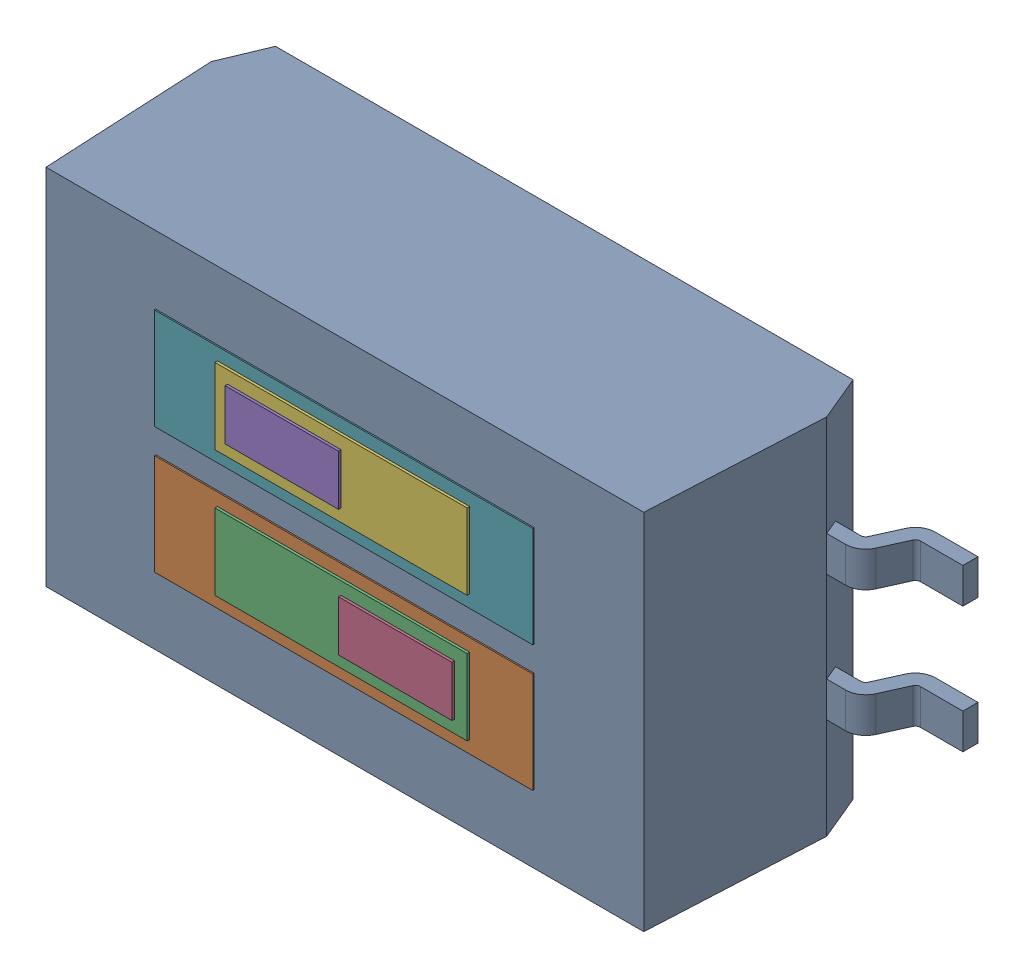
SolidWorks assembly S1, configuration Default. Lengths in mm.
Overall size (8.13 3.66 2.38).
13 component instances, 4 part files, 0 mates.
Components (placement in the parent):
- c-1571983-01-b-3d-1: c-1571983-01-b-3d [Default] at (63.7533 2.9696 0.571) x (0 1 0) z (0 0 1) size (3.66 8.13 2.31)
- 870942400-1: 870942400 [Default] at (63.7532 2.3346 1.27) size (3.81 1.02 1.07)
  - Extruded_11-1: Extruded_11 [Default] at origin size (3.81 1.02 1.07)
- 870942560-1: 870942560 [Default] at (63.7532 2.3346 1.27) size (2.54 0.76 1.09)
  - Extruded_12-1: Extruded_12 [Default] at origin size (2.54 0.76 1.09)
- 870942720-1: 870942720 [Default] at (64.3247 2.3346 1.27) size (1.14 0.51 1.12)
  - Extruded_13-1: Extruded_13 [Default] at origin size (1.14 0.51 1.12)
- 870942720-2: 870942720 [Default] at (63.1817 3.6046 1.27) size (1.14 0.51 1.12)
  - Extruded_13-1: Extruded_13 [Default] at origin size (1.14 0.51 1.12)
- 870942560-2: 870942560 [Default] at (63.7532 3.6046 1.27) size (2.54 0.76 1.09)
  - Extruded_12-1: Extruded_12 [Default] at origin size (2.54 0.76 1.09)
- 870942400-2: 870942400 [Default] at (63.7532 3.6046 1.27) size (3.81 1.02 1.07)
  - Extruded_11-1: Extruded_11 [Default] at origin size (3.81 1.02 1.07)
